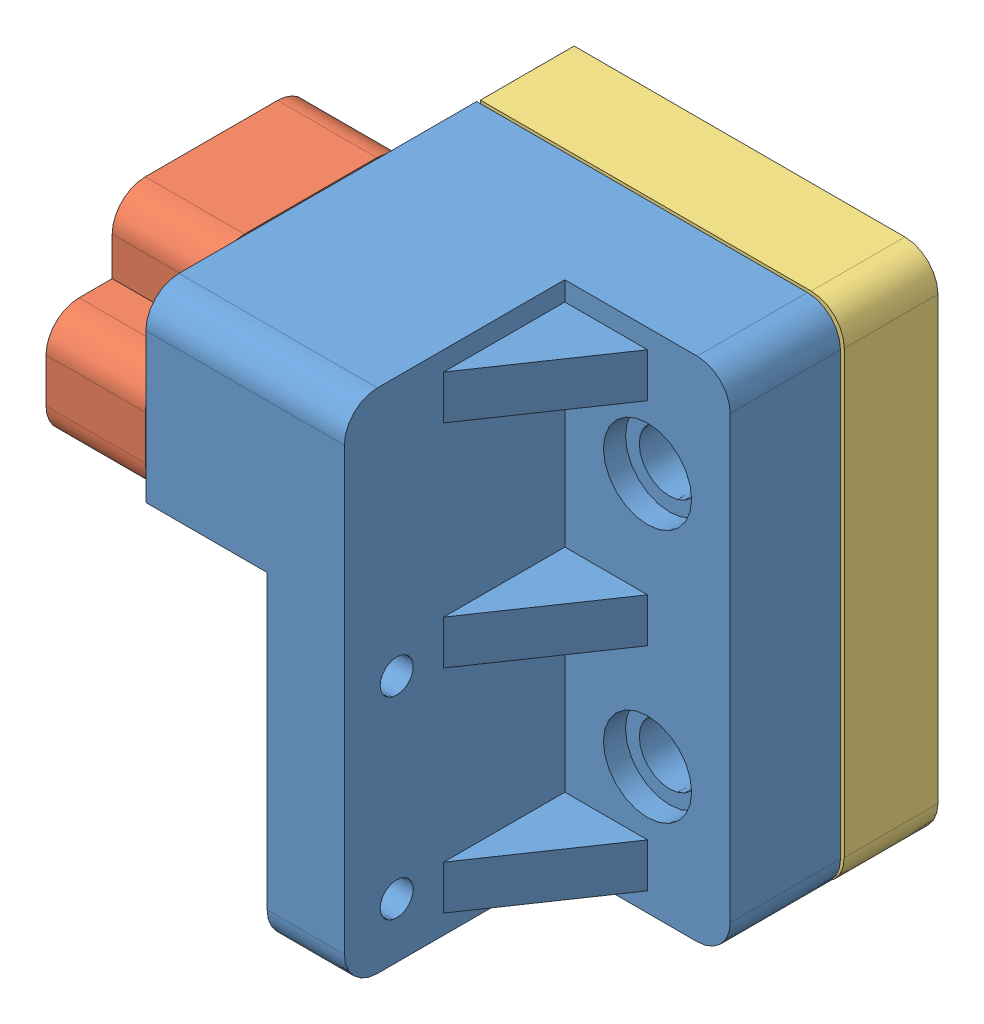
SolidWorks assembly Montagem1, configuration Valor predeterminado. Lengths in mm.
Overall size (42.11 46.07 38.81).
3 component instances, 3 part files, 0 mates.
Components (placement in the parent):
- suporteParede-1: suporteParede [Valor predeterminado] at (2.8599 -22.56 46) size (33 46 30)
- suportePorta-1: suportePorta [Valor predeterminado] at (-10.7112 16.9836 45.9843) x (-1 0 0) z (0 0 1) size (20 16.5 30)
- buchaSuporteParedeV2-1: buchaSuporteParedeV2 [Valor predeterminado] at (4.8947 0.4125 30.692) x (-1 0 0) z (0 -1 0) size (33 8.5 46)
